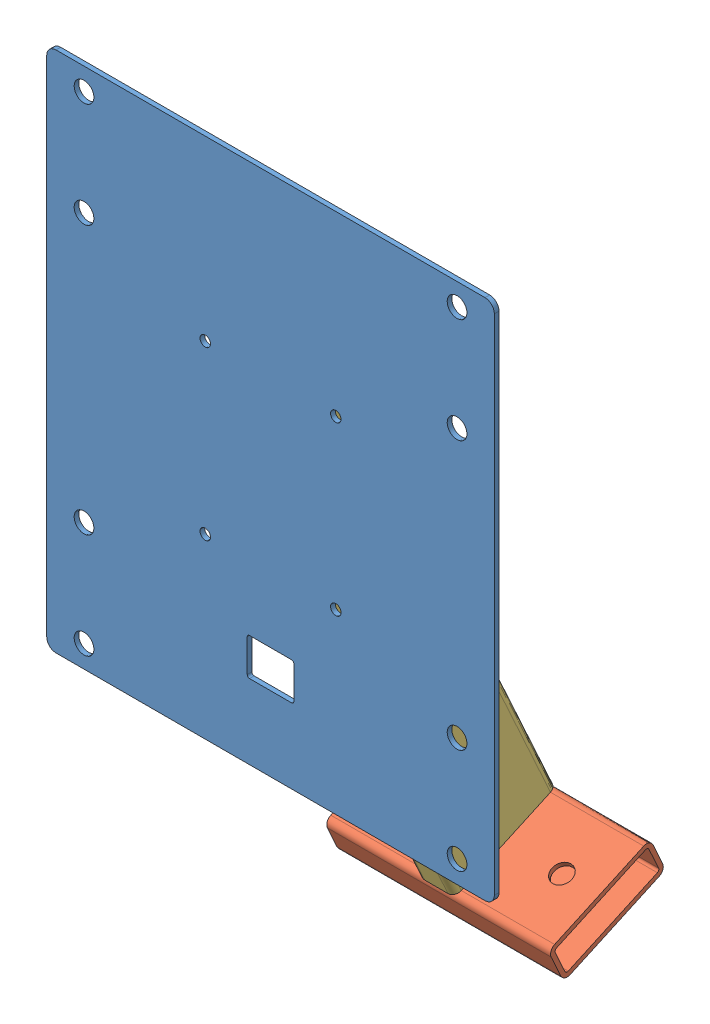
SolidWorks assembly GE-20089, configuration 20090. Lengths in mm.
Overall size (304.8 500.02 258.94).
3 component instances, 3 part files, 6 mates.
Components (placement in the parent):
- GE-20081-1: GE-20081 [Default<As Machined>] at origin size (304.8 355.6 3.17)
- GE-20086-1: GE-20086 [Default<As Machined>] at (0 -294.8651 -149.6616) x (1 0 0) z (0 -0.414693 0.909961) size (152.4 25.4 76.2)
- GE-20083-1: GE-20083 [Default<As Machined>] at (0 -86.848 -54.8627) x (0 -0.909961 -0.414693) z (-1 0 0) size (431.8 76.2 25.4)
Mates (geometry in assembly coordinates):
- Coincident10: coincident anti-aligned: plane of hardstop rev C_test part 001-1 through (0 0 0) normal (0 0 -1); plane of GE-20083-1 through (12.7 -86.848 0) normal (0 0 1)
- Width5: width aligned: plane of GE-20083-1 through (12.7 123.4375 4.3337) normal (1 0 0); plane of hardstop rev C_test part 001-1 through (-12.7 95.7879 65.0054) normal (-1 0 0); plane of GE-20083-1 through (152.4 177.8 3.175) normal (1 0 0); plane of hardstop rev C_test part 001-1 through (-152.4 177.8 3.175) normal (-1 0 0)
- Coincident11: coincident anti-aligned: plane of GE-20086-1 through (-76.2 -297.1334 -114.0592) normal (0 0.909961 0.414693); plane of GE-20083-1 through (-7.9375 -297.1334 -114.0592) normal (0 -0.909961 -0.414693)
- Coincident12: coincident aligned: plane of GE-20083-1 through (7.9375 125.4125 0) normal (0 0.414693 -0.909961); plane of GE-20086-1 through (-76.2 -286.2881 -187.6228) normal (0 0.414693 -0.909961)
- Width6: width anti-aligned: plane of GE-20083-1 through (-12.7 95.7879 65.0054) normal (-1 0 0); plane of GE-20086-1 through (12.7 123.4375 4.3337) normal (1 0 0); plane of GE-20083-1 through (76.2 -301.4671 -116.0342) normal (1 0 0); plane of GE-20086-1 through (-76.2 -301.4671 -116.0342) normal (-1 0 0)
- Distance3: distance = 52.3875 mm: line of hardstop rev C_test part 001-1 through (292.1 146.05 177.8) axis (0 -1 0); line of GE-20083-1 through (7.9375 125.4125 0) axis (-1 0 0)
